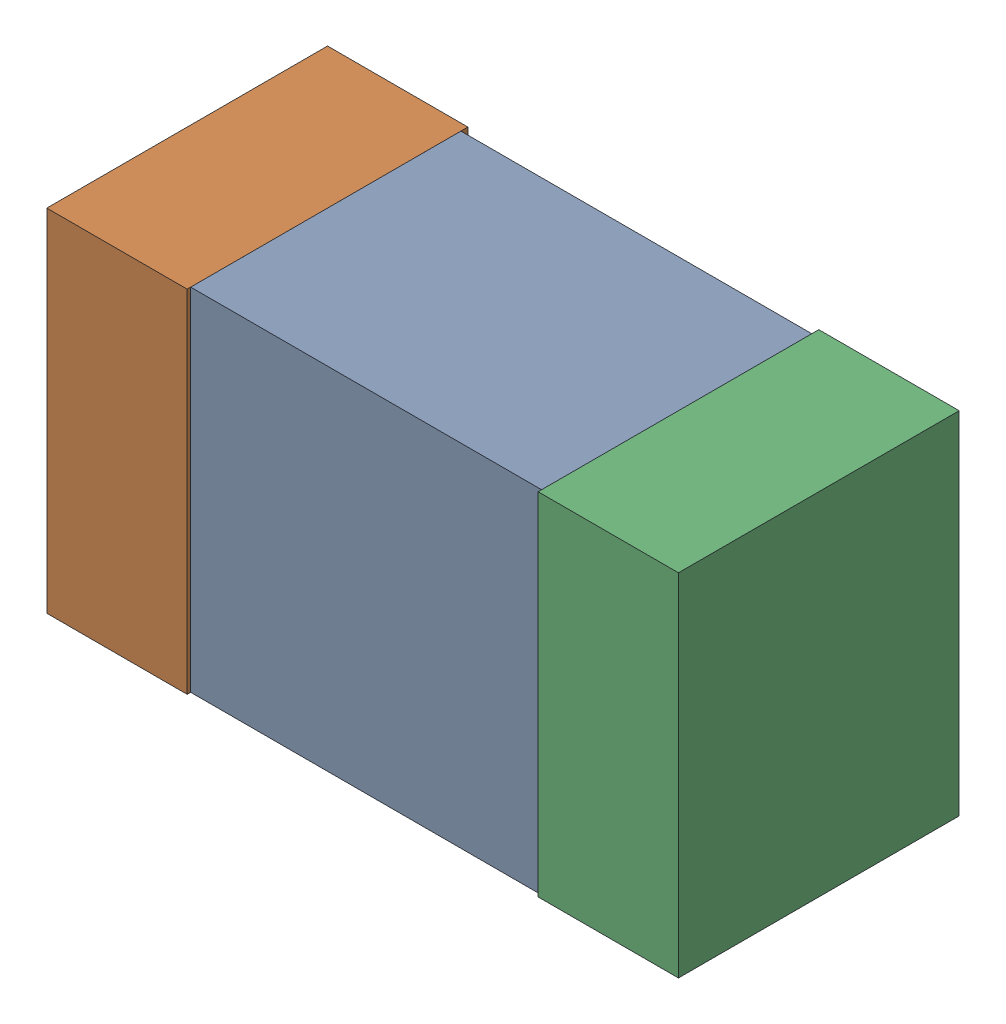
SolidWorks assembly L408PCB, configuration Default. Lengths in mm.
Overall size (1.8 1 0.8).
6 component instances, 2 part files, 0 mates.
Components (placement in the parent):
- 846483152-1: 846483152 [Default] at (130.5001 101.7999 -2.4438) size (1 1 0.77)
  - Extruded_3-1: Extruded_3 [Default] at origin size (1 1 0.77)
- 854785840-1: 854785840 [Default] at (129.8001 101.7999 -2.4638) size (0.4 1 0.8)
  - Extruded_4-1: Extruded_4 [Default] at origin size (0.4 1 0.8)
- 854785840-2: 854785840 [Default] at (131.2001 101.7999 -2.4638) size (0.4 1 0.8)
  - Extruded_4-1: Extruded_4 [Default] at origin size (0.4 1 0.8)
